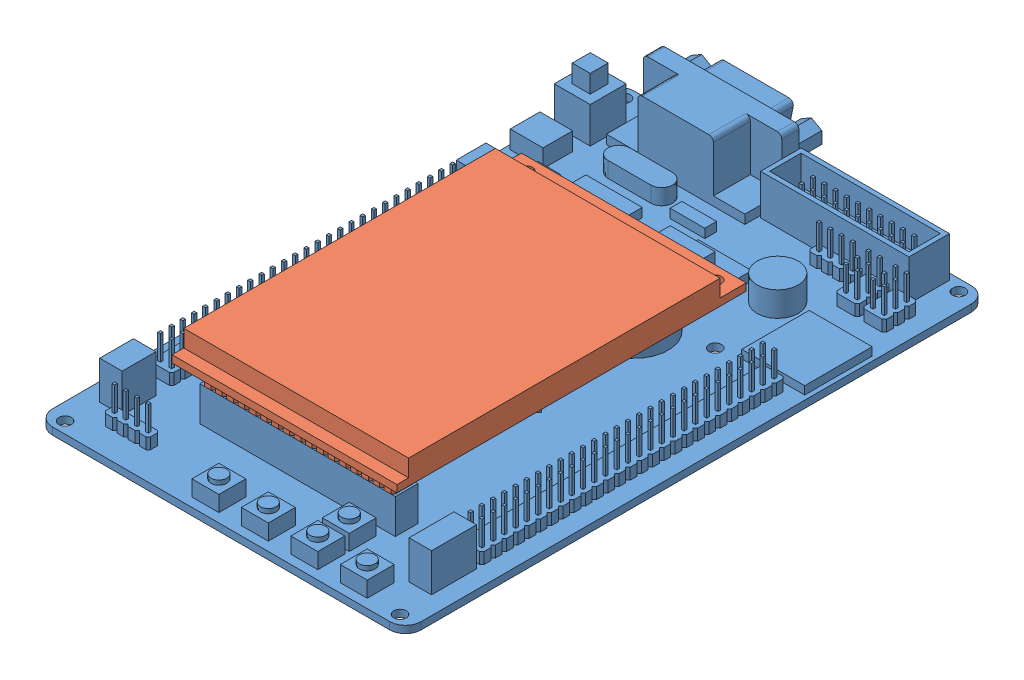
SolidWorks assembly MACM020100_STM32Assy, configuration 默认. Lengths in mm.
Overall size (82 19.9 134).
2 component instances, 2 part files, 3 mates.
Components (placement in the parent):
- MACM020101_STM32-1: MACM020101_STM32 [默认] at (-0.6393 -6.6301 138.9) size (82 16.3 134)
- MACM020102_LCD-1: MACM020102_LCD [默认] at (-0.6393 6.4699 150.65) size (50 15.8 77.7)
Mates (geometry in assembly coordinates):
- 同心1: concentric aligned: cylinder of MACM020101_STM32-1 through (20.3607 -5.0301 114.7) axis (0 -1 0) radius 1.4; cylinder of MACM020102_LCD-1 through (20.3607 8.0699 114.7) axis (0 -1 0) radius 1.4
- 重合1: coincident anti-aligned: plane of MACM020101_STM32-1 through (-0.6393 2.6699 138.9) normal (0 1 0); plane of MACM020102_LCD-1 through (-0.6393 2.6699 150.65) normal (0 -1 0)
- 同心2: concentric aligned: cylinder of MACM020101_STM32-1 through (-21.6393 -5.0301 114.7) axis (0 -1 0) radius 1.4; cylinder of MACM020102_LCD-1 through (-21.6393 8.0699 114.7) axis (0 -1 0) radius 1.4
